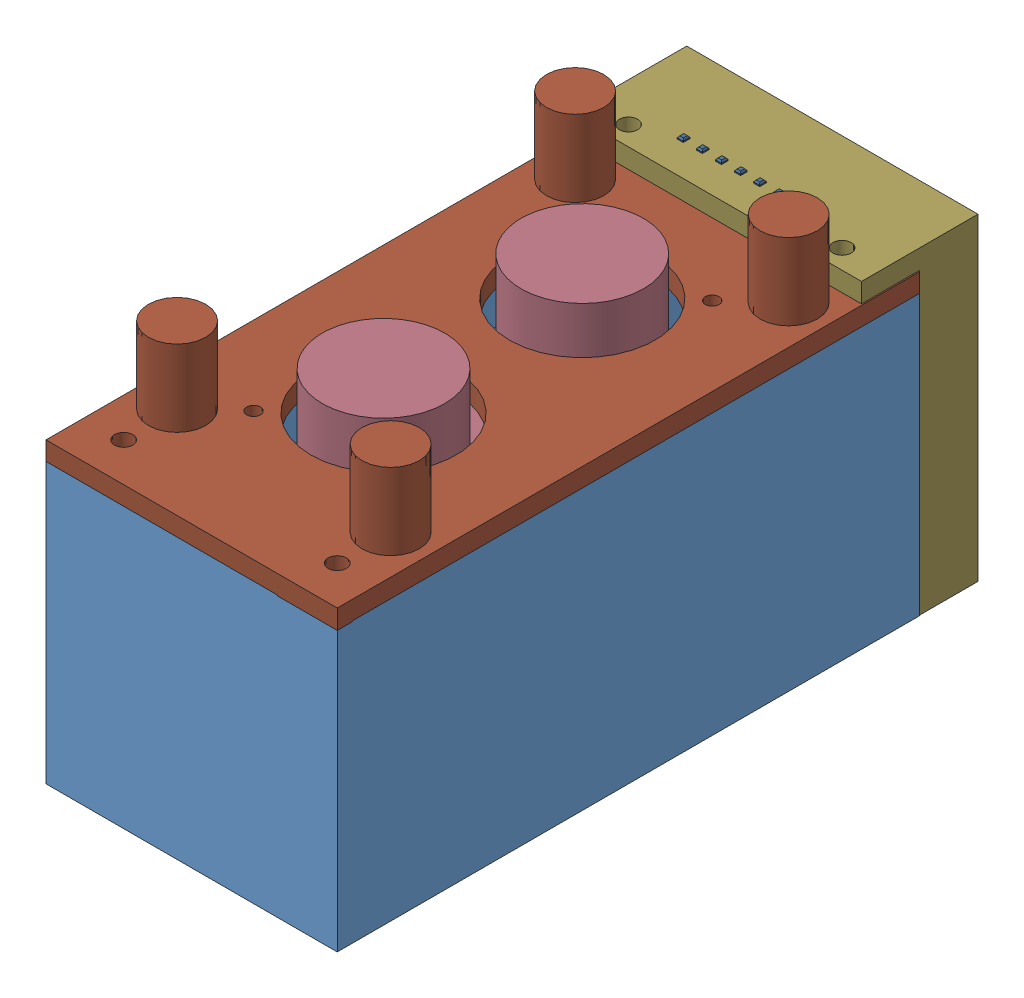
SolidWorks assembly Main, configuration Default. Lengths in mm.
Overall size (38.1 48.97 93.2).
89 component instances, 85 part files, 16 mates.
Components (placement in the parent):
- Mount-1: Mount [Default] at origin size (38.1 36.53 76.2)
- RaspBerryPi Pico W-1: RaspBerryPi Pico W [Default] at (0.0016 7.9566 -25.4949) x (-1 0 -0.00001) z (0 -1 0) size (21 52.34 3.69)
  - RaspBerryPi Pico W.step-1: RaspBerryPi Pico W.step [Default] at origin size (21 52.34 3.69)
    - PicoW v1.step-1: PicoW v1.step [Default] at (-10.5 -51 1.6) size (14.61 51.8 3.49)
      - Symbols.step-1: Symbols.step [Default] at origin size (14.61 51.8 3.49)
        - AVAGO_QSM.step-1: AVAGO_QSM.step [Default] at origin size (1.65 0.72 0.68)
        - BOURNS_SRN2512.step-1: BOURNS_SRN2512.step [Default] at origin size (2.29 2.79 1.22)
        - CAPC0603.step-1: CAPC0603.step [Default] at origin size (0.3 0.6 0.3)
        - CAPC0603 (1).step-1: CAPC0603 (1).step [Default] at origin size (0.6 0.3 0.3)
        - CAPC0603 (2).step-1: CAPC0603 (2).step [Default] at origin size (0.6 0.3 0.3)
        - CAPC0603 (3).step-1: CAPC0603 (3).step [Default] at origin size (0.6 0.3 0.3)
        - CAPC1005.step-1: CAPC1005.step [Default] at origin size (1 0.5 0.5)
        - CAPC1005 (1).step-1: CAPC1005 (1).step [Default] at origin size (0.5 1 0.5)
        - CAPC1005 (2).step-1: CAPC1005 (2).step [Default] at origin size (0.5 1 0.5)
        - CAPC1005 (3).step-1: CAPC1005 (3).step [Default] at origin size (0.5 1 0.5)
        - CAPC1005 (4).step-1: CAPC1005 (4).step [Default] at origin size (1 0.5 0.5)
        - CAPC1005 (5).step-1: CAPC1005 (5).step [Default] at origin size (1 0.5 0.5)
        - CAPC1005 (6).step-1: CAPC1005 (6).step [Default] at origin size (1 0.5 0.5)
        - CAPC1005 (7).step-1: CAPC1005 (7).step [Default] at origin size (1 0.5 0.5)
        - CAPC1005 (8).step-1: CAPC1005 (8).step [Default] at origin size (0.5 1 0.5)
        - CAPC1005 (9).step-1: CAPC1005 (9).step [Default] at origin size (1 0.5 0.5)
        - CAPC1005X55N.step-1: CAPC1005X55N.step [Default] at origin size (1 0.5 0.5)
        - CAPC1005X55N (1).step-1: CAPC1005X55N (1).step [Default] at origin size (0.5 1 0.5)
        - CAPC1005X55N (2).step-1: CAPC1005X55N (2).step [Default] at origin size (1 0.5 0.5)
        - CAPC1608X90N.step-1: CAPC1608X90N.step [Default] at origin size (1.6 0.8 0.8)
        - CAPC1608X90N (1).step-1: CAPC1608X90N (1).step [Default] at origin size (0.8 1.6 0.8)
        - CAPC2012.step-1: CAPC2012.step [Default] at origin size (2 1.25 0.6)
        - CAPC2012 (1).step-1: CAPC2012 (1).step [Default] at origin size (2 1.25 0.6)
        - CAPC2012 (2).step-1: CAPC2012 (2).step [Default] at origin size (2 1.25 0.6)
        - FCI_10103594-0001LF.step-1: FCI_10103594-0001LF.step [Default] at origin size (7.99 6.06 3.49)
        - M0603_PICO.step-1: M0603_PICO.step [Default] at origin size (0.6 0.3 0.3)
        - M0603_PICO (1).step-1: M0603_PICO (1).step [Default] at origin size (0.63 0.63 0.3)
        - M0603_PICO (2).step-1: M0603_PICO (2).step [Default] at origin size (0.6 0.3 0.3)
        - M0603_PICO (3).step-1: M0603_PICO (3).step [Default] at origin size (0.6 0.3 0.3)
        - M0603_PICO (4).step-1: M0603_PICO (4).step [Default] at origin size (0.6 0.3 0.3)
        - M0603_PICO (5).step-1: M0603_PICO (5).step [Default] at origin size (0.3 0.6 0.3)
        - M0603_PICO (6).step-1: M0603_PICO (6).step [Default] at origin size (0.3 0.6 0.3)
        - M0603_PICO (7).step-1: M0603_PICO (7).step [Default] at origin size (0.3 0.6 0.3)
        - M0603_PICO (8).step-1: M0603_PICO (8).step [Default] at origin size (0.3 0.6 0.3)
        - M0603_PICO (9).step-1: M0603_PICO (9).step [Default] at origin size (0.3 0.6 0.3)
        - M0603_PICO (10).step-1: M0603_PICO (10).step [Default] at origin size (0.3 0.6 0.3)
        - M0603_PICO (11).step-1: M0603_PICO (11).step [Default] at origin size (0.3 0.6 0.3)
        - M0603_PICO (12).step-1: M0603_PICO (12).step [Default] at origin size (0.3 0.6 0.3)
        - M0603_PICO (13).step-1: M0603_PICO (13).step [Default] at origin size (0.3 0.6 0.3)
        - M0603_PICO (14).step-1: M0603_PICO (14).step [Default] at origin size (0.3 0.6 0.3)
        - M0603_PICO (15).step-1: M0603_PICO (15).step [Default] at origin size (0.3 0.6 0.3)
        - M0603_PICO (16).step-1: M0603_PICO (16).step [Default] at origin size (0.3 0.6 0.3)
        - RESC0603.step-1: RESC0603.step [Default] at origin size (0.6 0.3 0.15)
        - RESC0603 (1).step-1: RESC0603 (1).step [Default] at origin size (0.6 0.3 0.15)
        - RESC0603 (2).step-1: RESC0603 (2).step [Default] at origin size (0.6 0.3 0.15)
        - RESC0603 (3).step-1: RESC0603 (3).step [Default] at origin size (0.3 0.6 0.15)
        - RESC1005.step-1: RESC1005.step [Default] at origin size (0.5 1 0.35)
        - RESC1608.step-1: RESC1608.step [Default] at origin size (1.6 0.8 0.45)
        - RF0603.step-1: RF0603.step [Default] at origin size (0.6 0.3 0.3)
        - RF0603 (1).step-1: RF0603 (1).step [Default] at origin size (0.63 0.63 0.3)
        - RF0603 (2).step-1: RF0603 (2).step [Default] at origin size (0.6 0.3 0.3)
        - RF0603 (3).step-1: RF0603 (3).step [Default] at origin size (0.3 0.6 0.3)
        - RF0603 (4).step-1: RF0603 (4).step [Default] at origin size (0.3 0.6 0.3)
        - RF_SHIELD_PICOW.step-1: RF_SHIELD_PICOW.step [Default] at origin size (12 10 1.7)
        - RPI_RP2040.step-1: RPI_RP2040.step [Default] at origin size (7 7 0.9)
        - SOD123FL.step-1: SOD123FL.step [Default] at origin size (1.65 3.6 0.98)
        - SONY0603.step-1: SONY0603.step [Default] at origin size (0.3 0.6 0.3)
        - SONY0603 (1).step-1: SONY0603 (1).step [Default] at origin size (0.6 0.3 0.3)
        - SONY0603 (2).step-1: SONY0603 (2).step [Default] at origin size (0.63 0.63 0.3)
        - SONY0603 (3).step-1: SONY0603 (3).step [Default] at origin size (0.3 0.6 0.3)
        - SONY0603 (4).step-1: SONY0603 (4).step [Default] at origin size (0.6 0.3 0.3)
        - SONY0603 (5).step-1: SONY0603 (5).step [Default] at origin size (0.3 0.6 0.3)
        - SONY0603 (6).step-1: SONY0603 (6).step [Default] at origin size (0.6 0.3 0.3)
        - SONY0603 (7).step-1: SONY0603 (7).step [Default] at origin size (0.6 0.3 0.3)
        - SONY0603 (8).step-1: SONY0603 (8).step [Default] at origin size (0.6 0.3 0.3)
        - SONY0603 (9).step-1: SONY0603 (9).step [Default] at origin size (0.6 0.3 0.3)
        - SONY0603 (10).step-1: SONY0603 (10).step [Default] at origin size (0.3 0.6 0.3)
        - SONY0603 (11).step-1: SONY0603 (11).step [Default] at origin size (0.3 0.6 0.3)
        - SONY0603 (12).step-1: SONY0603 (12).step [Default] at origin size (0.6 0.3 0.3)
        - SONY0603 (13).step-1: SONY0603 (13).step [Default] at origin size (0.3 0.6 0.3)
        - SONY0603 (14).step-1: SONY0603 (14).step [Default] at origin size (0.3 0.6 0.3)
        - SOT50P160X90-3N.step-1: SOT50P160X90-3N.step [Default] at origin size (1.6 1.6 0.8)
        - USON_2X3MM.step-1: USON_2X3MM.step [Default] at origin size (3 2 0.6)
        - XTAL320X250X100.step-1: XTAL320X250X100.step [Default] at origin size (3.2 2.5 0.92)
    - BOOTSEL v3.step-1: BOOTSEL v3.step [Default] at (-3.55 -9.9 1.6) size (3.24 4.29 2.5)
    - RaspBerryPi Pico_CircuitBoard_logo v15.step-1: RaspBerryPi Pico_CircuitBoard_logo v15.step [Default] at (0.0013 0.005 0.0066) size (21 51 1.01)
    - RaspBerryPi Pico W.step-1: RaspBerryPi Pico W.step [Default] at origin size (1.6 1.6 1)
    - RaspBerryPi Pico W-0.step-1: RaspBerryPi Pico W-0.step [Default] at origin size (1.51 0.64 0.01)
    - RaspBerryPi Pico W-1.step-1: RaspBerryPi Pico W-1.step [Default] at origin size (1.5 1.18 0.01)
- ADXL326-1: ADXL326 [Default] at (9.525 19.5326 15.24) x (-1 0 0) z (0 0 -1) size (19.05 3.3 19.05)
- Arducam MINI OV2640-1: Arducam MINI OV2640 [Default] at (-0.0003 20.0259 -39.1) x (1 0 0) z (0 0 -1) size (25 38.5 20.54)
- Mount Cover-1: Mount Cover [Default] at (0 36.4273 0) size (38.1 12.54 76.2)
- MountCameraCover-1: MountCameraCover [Default] at (0 0.0681 -38.1) x (-1 0 0) z (0 0 -1) size (38.1 41.61 15.24)
- HCRS04-1: HCRS04 [Default] at (-10 28.8073 -22.5) x (0 0 1) z (-1 0 0) size (45 15.24 20)
Mates (geometry in assembly coordinates):
- Coincident2: coincident anti-aligned: plane of Mount-1 through (0 0 -38.1) normal (0 0 -1); plane of Arducam MINI OV2640-1 through (-12.5003 36.5259 -38.1) normal (0 0 1)
- Concentric4: concentric anti-aligned: cylinder of Mount-1 through (10.3149 5.715 -35.56) axis (0 0 -1) radius 1.5011; cylinder of Arducam MINI OV2640-1 through (10.3144 5.715 -38.6) axis (0 0 1) radius 1.5
- Concentric5: concentric aligned: cylinder of Mount-1 through (-10.3149 5.715 -35.56) axis (0 0 -1) radius 1.5011; cylinder of Arducam MINI OV2640-1 through (-10.3149 5.715 -38.6) axis (0 0 -1) radius 1.5
- Concentric6: concentric anti-aligned: cylinder of Mount-1 through (-5.6998 2.54 -23.5001) axis (0 1 0) radius 1.2; cylinder of RaspBerryPi Pico W-1/RaspBerryPi Pico W.step-1/RaspBerryPi Pico_CircuitBoard_logo v15.step-1 through (-5.6998 6.95 -23.5) axis (0 -1 0) radius 1.05
- Distance1: distance = 3.81 mm anti-aligned: plane of RaspBerryPi Pico W-1/RaspBerryPi Pico W.step-1/RaspBerryPi Pico_CircuitBoard_logo v15.step-1 through (0 6.35 0.57) normal (0 -1 0); plane of Mount-1 through (0 2.54 0) normal (0 1 0)
- Concentric7: concentric anti-aligned: cylinder of Mount-1 through (5.6998 2.54 23.5001) axis (0 1 0) radius 1.2; cylinder of RaspBerryPi Pico W-1/RaspBerryPi Pico W.step-1/RaspBerryPi Pico_CircuitBoard_logo v15.step-1 through (5.6998 6.95 23.5001) axis (0 -1 0) radius 1.05
- Concentric9: concentric aligned: cylinder of Mount-1 through (13.97 36.5252 -33.02) axis (0 1 0) radius 1.2; cylinder of Mount Cover-1 through (13.97 38.9673 -33.02) axis (0 1 0) radius 1.2
- Concentric10: concentric aligned: cylinder of Mount-1 through (-13.97 36.5252 -33.02) axis (0 1 0) radius 1.2; cylinder of Mount Cover-1 through (-13.97 38.9673 -33.02) axis (0 1 0) radius 1.2
- Coincident9: coincident anti-aligned: plane of Mount-1 through (0 19.5326 0) normal (0 1 0); plane of ADXL326-1 through (6.985 19.5326 31.75) normal (0 -1 0)
- Concentric15: concentric aligned: cylinder of Mount-1 through (-6.985 16.9926 31.75) axis (0 1 0) radius 1.016; cylinder of ADXL326-1 through (-6.985 19.5326 31.75) axis (0 1 0) radius 1.016
- Concentric16: concentric aligned: cylinder of Mount-1 through (6.985 16.9926 31.75) axis (0 1 0) radius 1.016; cylinder of ADXL326-1 through (6.985 19.5326 31.75) axis (0 1 0) radius 1.016
- Coincident16: coincident anti-aligned: plane of Mount Cover-1 through (-19.05 38.9673 -38.1) normal (0 0 -1); plane of MountCameraCover-1 through (0 0.0681 -38.1) normal (0 0 1)
- Concentric17: concentric anti-aligned: cylinder of Mount Cover-1 through (0 38.9673 -13) axis (0 1 0) radius 9.5; cylinder of HCRS04-1 through (0 44.0473 -13) axis (0 -1 0) radius 8
- Concentric18: concentric anti-aligned: cylinder of Mount Cover-1 through (0 38.9673 13) axis (0 1 0) radius 9.5; cylinder of HCRS04-1 through (0 44.0473 13) axis (0 -1 0) radius 8
- Distance2: distance = 5.08 mm anti-aligned: plane of Mount Cover-1 through (0 36.4273 0) normal (0 -1 0); plane of HCRS04-1 through (-10 31.3473 -22.5) normal (0 1 0)
- Concentric21: concentric aligned: cylinder of Mount Cover-1 through (13.97 38.9673 -33.02) axis (0 1 0) radius 1.2; cylinder of MountCameraCover-1 through (13.97 41.6733 -33.02) axis (0 1 0) radius 1.2
